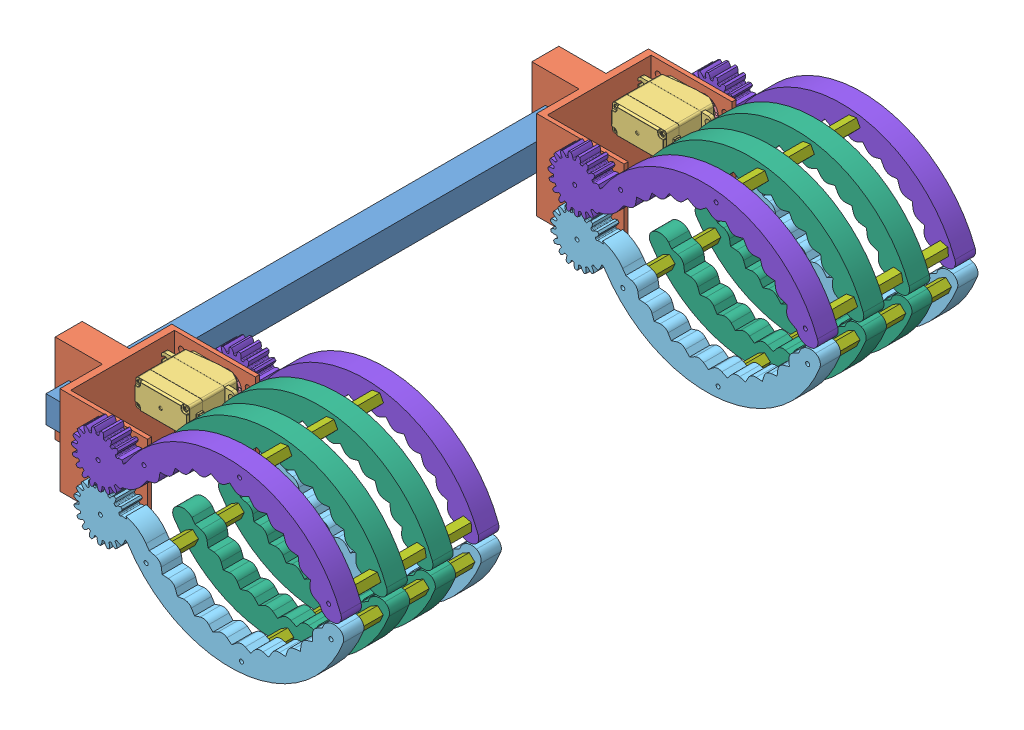
SolidWorks assembly 装配体4, configuration Default. Lengths in mm.
Overall size (266.2 159.66 472.45).
65 component instances, 8 part files, 6 mates.
Components (placement in the parent):
- 6.横杆的简易模型-1: 6.横杆的简易模型 [默认] at origin size (20 20 400)
- 装配体_爪子加舵机-1: 装配体_爪子加舵机 [Default] at (2.5929 19.9341 -22.1435) size (266.2 159.66 118.7)
  - 3.固定舵机盘-1: 3.固定舵机盘 [默认] at origin size (100 66 87)
  - 4.35KGservo-1: 4.35KGservo [默认] at (35.5165 11.5325 23.201) x (1 0 0) z (0 1 0) size (62.21 45.03 20.04)
  - 5.舵机圆形头-1: 5.舵机圆形头 [默认] at (35.5165 11.5325 23.6787) x (1 0 0) z (0 1 0) size (19.5 4.4 19.5)
  - 装配体_右爪子-1: 装配体_右爪子 [Default] at (135.3421 -3.8963 -6.499) x (-0.1033 0.99465 0) z (0 0 -1) size (79.93 200.48 117)
    - 1_2.右爪子表面_打印两个-1: 1_2.右爪子表面_打印两个 [Varsayılan] at origin size (79.93 200.48 15)
    - 1_3.爪子中间_打印四个-1: 1_3.爪子中间_打印四个 [Varsayılan] at (-3.0019 8.3684 -34) size (58.35 161.77 15)
    - 2.铜柱连接件-1: 2.铜柱连接件 [Varsayılan] at (-63.8128 8.351 -21.5) size (9.37 9.17 19)
    - 2.铜柱连接件-2: 2.铜柱连接件 [Varsayılan] at (-23.3138 79.3592 -21.5) size (9.37 9.17 19)
    - 2.铜柱连接件-3: 2.铜柱连接件 [Varsayılan] at (-23.3138 79.3592 -55.5) size (9.37 9.17 19)
    - 2.铜柱连接件-4: 2.铜柱连接件 [Varsayılan] at (-28.743 -59.1519 -21.5) size (9.37 9.17 19)
    - 2.铜柱连接件-5: 2.铜柱连接件 [Varsayılan] at (-28.743 -59.1519 -55.5) size (9.37 9.17 19)
    - 2.铜柱连接件-6: 2.铜柱连接件 [Varsayılan] at (-23.3138 79.3592 -89.5) size (9.37 9.17 19)
    - 2.铜柱连接件-7: 2.铜柱连接件 [Varsayılan] at (-28.743 -59.1519 -89.5) size (9.37 9.17 19)
    - 2.铜柱连接件-8: 2.铜柱连接件 [Varsayılan] at (-63.8128 8.351 -55.5) size (9.37 9.17 19)
    - 2.铜柱连接件-9: 2.铜柱连接件 [Varsayılan] at (-63.8128 8.351 -70.5) x (-0.498458 -0.866914 0) z (0 0 -1) size (9.37 9.17 19)
    - 1_3.爪子中间_打印四个-2: 1_3.爪子中间_打印四个 [Varsayılan] at (-3.0019 8.3684 -68) size (58.35 161.77 15)
    - 1_2.右爪子表面_打印两个-2: 1_2.右爪子表面_打印两个 [Varsayılan] at (0 0 -102) size (79.93 200.48 15)
  - 装配体_左爪子-1: 装配体_左爪子 [Default] at (135.182 -9.7505 87.201) x (-0.109747 -0.99396 0) z (0 0 1) size (79.66 200.49 117)
    - 1_1.左爪子表面_打印两个-1: 1_1.左爪子表面_打印两个 [Varsayılan] at origin size (79.66 200.49 15)
    - 1_3.爪子中间_打印四个-1: 1_3.爪子中间_打印四个 [Varsayılan] at (-3.003 8.3732 -34) size (58.35 161.77 15)
    - 2.铜柱连接件-1: 2.铜柱连接件 [Varsayılan] at (-28.744 -59.1471 -21.5) x (0.366858 -0.930277 0) z (0 0 1) size (9.37 9.17 19)
    - 2.铜柱连接件-2: 2.铜柱连接件 [Varsayılan] at (-63.8139 8.3557 -21.5) x (0.366858 -0.930277 0) z (0 0 1) size (9.37 9.17 19)
    - 2.铜柱连接件-3: 2.铜柱连接件 [Varsayılan] at (-23.3149 79.364 -21.5) x (0.366858 -0.930277 0) z (0 0 1) size (9.37 9.17 19)
    - 2.铜柱连接件-4: 2.铜柱连接件 [Varsayılan] at (-23.3149 79.364 -55.5) x (-0.923835 -0.38279 0) z (0 0 1) size (9.37 9.17 19)
    - 2.铜柱连接件-5: 2.铜柱连接件 [Varsayılan] at (-63.8139 8.3557 -55.5) x (0.366858 -0.930277 0) z (0 0 1) size (9.37 9.17 19)
    - 2.铜柱连接件-6: 2.铜柱连接件 [Varsayılan] at (-28.744 -59.1471 -55.5) x (0.366858 -0.930277 0) z (0 0 1) size (9.37 9.17 19)
    - 2.铜柱连接件-7: 2.铜柱连接件 [Varsayılan] at (-28.744 -59.1471 -89.5) x (0.366858 -0.930277 0) z (0 0 1) size (9.37 9.17 19)
    - 2.铜柱连接件-8: 2.铜柱连接件 [Varsayılan] at (-23.3149 79.364 -89.5) x (-0.960896 -0.276909 0) z (0 0 1) size (9.37 9.17 19)
    - 2.铜柱连接件-9: 2.铜柱连接件 [Varsayılan] at (-63.8139 8.3557 -89.5) x (0.366858 -0.930277 0) z (0 0 1) size (9.37 9.17 19)
    - 1_3.爪子中间_打印四个-2: 1_3.爪子中间_打印四个 [Varsayılan] at (-3.003 8.3732 -68) size (58.35 161.77 15)
    - 1_1.左爪子表面_打印两个-2: 1_1.左爪子表面_打印两个 [Varsayılan] at (0 0 -102) size (79.66 200.49 15)
- 装配体_爪子加舵机-2: 装配体_爪子加舵机 [Default] at (2.5929 19.9341 331.603) size (266.2 159.66 118.7)
  - 3.固定舵机盘-1: 3.固定舵机盘 [默认] at origin size (100 66 87)
  - 4.35KGservo-1: 4.35KGservo [默认] at (35.5165 11.5325 23.201) x (1 0 0) z (0 1 0) size (62.21 45.03 20.04)
  - 5.舵机圆形头-1: 5.舵机圆形头 [默认] at (35.5165 11.5325 23.6787) x (1 0 0) z (0 1 0) size (19.5 4.4 19.5)
  - 装配体_右爪子-1: 装配体_右爪子 [Default] at (135.3421 -3.8963 -6.499) x (-0.1033 0.99465 0) z (0 0 -1) size (79.93 200.48 117)
    - 1_2.右爪子表面_打印两个-1: 1_2.右爪子表面_打印两个 [Varsayılan] at origin size (79.93 200.48 15)
    - 1_3.爪子中间_打印四个-1: 1_3.爪子中间_打印四个 [Varsayılan] at (-3.0019 8.3684 -34) size (58.35 161.77 15)
    - 2.铜柱连接件-1: 2.铜柱连接件 [Varsayılan] at (-63.8128 8.351 -21.5) size (9.37 9.17 19)
    - 2.铜柱连接件-2: 2.铜柱连接件 [Varsayılan] at (-23.3138 79.3592 -21.5) size (9.37 9.17 19)
    - 2.铜柱连接件-3: 2.铜柱连接件 [Varsayılan] at (-23.3138 79.3592 -55.5) size (9.37 9.17 19)
    - 2.铜柱连接件-4: 2.铜柱连接件 [Varsayılan] at (-28.743 -59.1519 -21.5) size (9.37 9.17 19)
    - 2.铜柱连接件-5: 2.铜柱连接件 [Varsayılan] at (-28.743 -59.1519 -55.5) size (9.37 9.17 19)
    - 2.铜柱连接件-6: 2.铜柱连接件 [Varsayılan] at (-23.3138 79.3592 -89.5) size (9.37 9.17 19)
    - 2.铜柱连接件-7: 2.铜柱连接件 [Varsayılan] at (-28.743 -59.1519 -89.5) size (9.37 9.17 19)
    - 2.铜柱连接件-8: 2.铜柱连接件 [Varsayılan] at (-63.8128 8.351 -55.5) size (9.37 9.17 19)
    - 2.铜柱连接件-9: 2.铜柱连接件 [Varsayılan] at (-63.8128 8.351 -70.5) x (-0.498458 -0.866914 0) z (0 0 -1) size (9.37 9.17 19)
    - 1_3.爪子中间_打印四个-2: 1_3.爪子中间_打印四个 [Varsayılan] at (-3.0019 8.3684 -68) size (58.35 161.77 15)
    - 1_2.右爪子表面_打印两个-2: 1_2.右爪子表面_打印两个 [Varsayılan] at (0 0 -102) size (79.93 200.48 15)
  - 装配体_左爪子-1: 装配体_左爪子 [Default] at (135.182 -9.7505 87.201) x (-0.109747 -0.99396 0) z (0 0 1) size (79.66 200.49 117)
    - 1_1.左爪子表面_打印两个-1: 1_1.左爪子表面_打印两个 [Varsayılan] at origin size (79.66 200.49 15)
    - 1_3.爪子中间_打印四个-1: 1_3.爪子中间_打印四个 [Varsayılan] at (-3.003 8.3732 -34) size (58.35 161.77 15)
    - 2.铜柱连接件-1: 2.铜柱连接件 [Varsayılan] at (-28.744 -59.1471 -21.5) x (0.366858 -0.930277 0) z (0 0 1) size (9.37 9.17 19)
    - 2.铜柱连接件-2: 2.铜柱连接件 [Varsayılan] at (-63.8139 8.3557 -21.5) x (0.366858 -0.930277 0) z (0 0 1) size (9.37 9.17 19)
    - 2.铜柱连接件-3: 2.铜柱连接件 [Varsayılan] at (-23.3149 79.364 -21.5) x (0.366858 -0.930277 0) z (0 0 1) size (9.37 9.17 19)
    - 2.铜柱连接件-4: 2.铜柱连接件 [Varsayılan] at (-23.3149 79.364 -55.5) x (-0.923835 -0.38279 0) z (0 0 1) size (9.37 9.17 19)
    - 2.铜柱连接件-5: 2.铜柱连接件 [Varsayılan] at (-63.8139 8.3557 -55.5) x (0.366858 -0.930277 0) z (0 0 1) size (9.37 9.17 19)
    - 2.铜柱连接件-6: 2.铜柱连接件 [Varsayılan] at (-28.744 -59.1471 -55.5) x (0.366858 -0.930277 0) z (0 0 1) size (9.37 9.17 19)
    - 2.铜柱连接件-7: 2.铜柱连接件 [Varsayılan] at (-28.744 -59.1471 -89.5) x (0.366858 -0.930277 0) z (0 0 1) size (9.37 9.17 19)
    - 2.铜柱连接件-8: 2.铜柱连接件 [Varsayılan] at (-23.3149 79.364 -89.5) x (-0.960896 -0.276909 0) z (0 0 1) size (9.37 9.17 19)
    - 2.铜柱连接件-9: 2.铜柱连接件 [Varsayılan] at (-63.8139 8.3557 -89.5) x (0.366858 -0.930277 0) z (0 0 1) size (9.37 9.17 19)
    - 1_3.爪子中间_打印四个-2: 1_3.爪子中间_打印四个 [Varsayılan] at (-3.003 8.3732 -68) size (58.35 161.77 15)
    - 1_1.左爪子表面_打印两个-2: 1_1.左爪子表面_打印两个 [Varsayılan] at (0 0 -102) size (79.66 200.49 15)
Mates (geometry in assembly coordinates):
- 重合1: coincident anti-aligned: plane of 6.横杆的简易模型-1 through (-21.8405 23.4666 400) normal (0 1 0); plane of 装配体_爪子加舵机-1/3.固定舵机盘-1 through (-1.8405 23.4666 77.8575) normal (0 -1 0)
- 重合2: coincident anti-aligned: plane of 6.横杆的简易模型-1 through (-21.8405 23.4666 400) normal (-1 0 0); plane of 装配体_爪子加舵机-1/3.固定舵机盘-1 through (-21.8405 23.4666 77.8575) normal (1 0 0)
- 锁定1: lock: unknown of 6.横杆的简易模型-1; unknown of 装配体_爪子加舵机-1/3.固定舵机盘-1
- 重合4: coincident: plane of 6.横杆的简易模型-1 through (-21.8405 23.4666 400) normal (-1 0 0); plane of 装配体_爪子加舵机-2/3.固定舵机盘-1 through (-21.8405 23.4666 431.604) normal (1 0 0)
- 重合5: coincident: plane of 6.横杆的简易模型-1 through (-21.8405 23.4666 400) normal (0 1 0); plane of 装配体_爪子加舵机-2/3.固定舵机盘-1 through (-1.8405 23.4666 431.604) normal (0 -1 0)
- 锁定2: lock: unknown of 6.横杆的简易模型-1; unknown of 装配体_爪子加舵机-2/3.固定舵机盘-1
